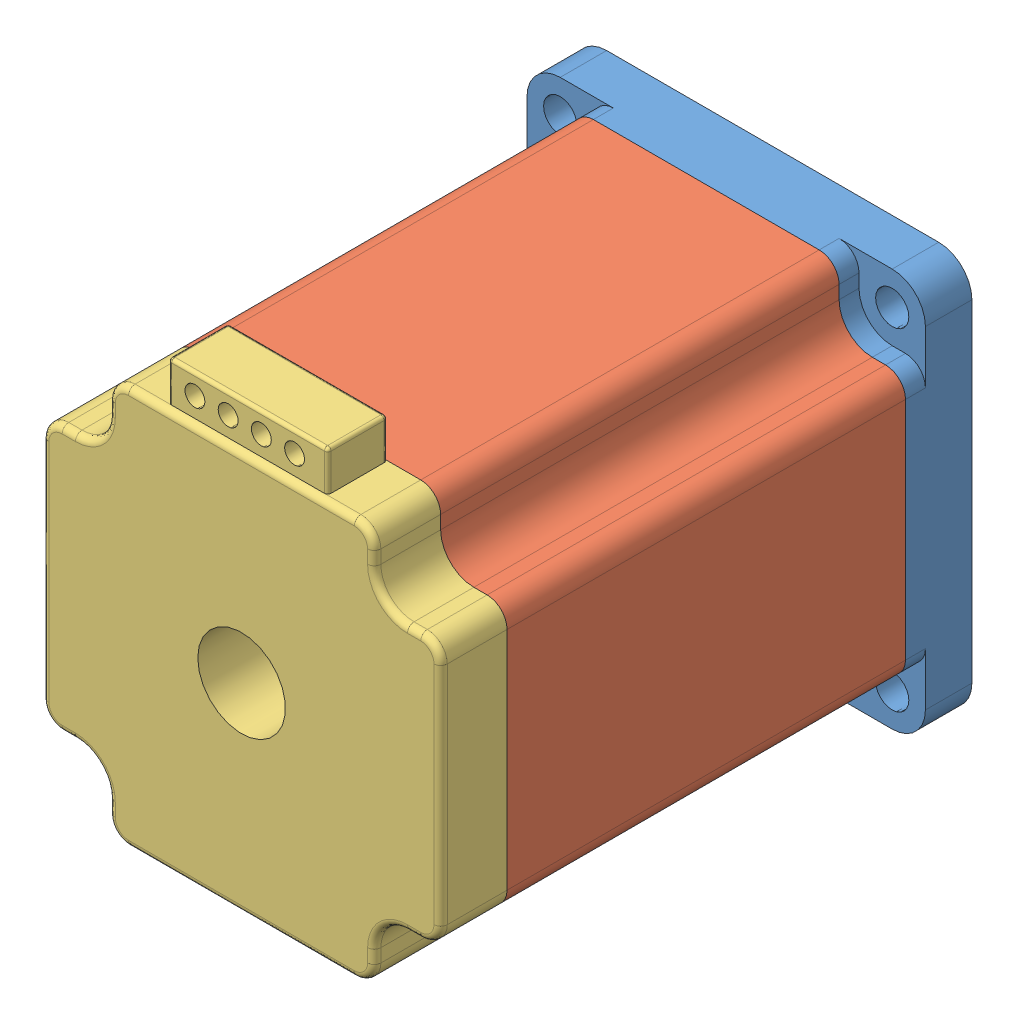
SolidWorks assembly nema 24, configuration Varsayılan. Lengths in mm.
Overall size (60 66 81.2).
3 component instances, 3 part files, 4 mates.
Components (placement in the parent):
- one-1: one [Varsayılan] at (11.8707 2.1079 0) size (60 60 11.2)
- midd-1: midd [Varsayılan] at (33.4607 -1.73 10) size (60 60 60)
- last one-1: last one [Varsayılan] at (45.1146 -5.7215 70) size (60 66 10)
Mates (geometry in assembly coordinates):
- Çakışık1: coincident: moEndPointRef_w of one-1; moEndPointRef_w of midd-1
- Çakışık2: coincident aligned: circle of one-1; circle of midd-1
- Çakışık3: coincident aligned: circle of midd-1; circle of last one-1
- Çakışık4: coincident aligned: line of midd-1 through (38.1609 -14.9983 70) axis (0 1 0); line of last one-1 through (38.1609 -14.9983 70) axis (0 1 0)
